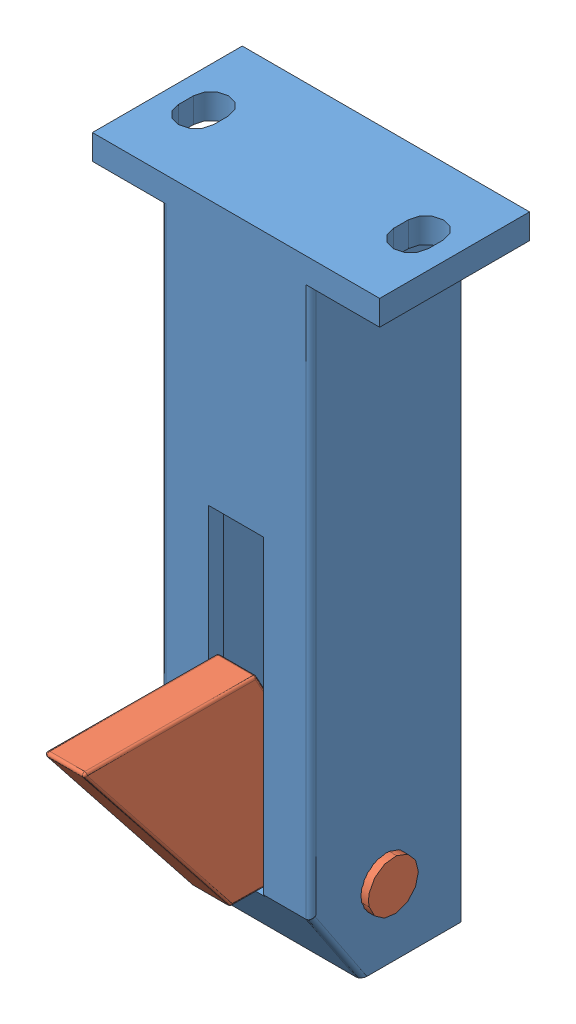
SolidWorks assembly 防坠安全器, configuration Default. Lengths in mm.
Overall size (115 260 128.97).
2 component instances, 2 part files, 4 mates.
Components (placement in the parent):
- 防坠器外壳-1: 防坠器外壳 [Default] at (141.0798 312.8832 146.3772) size (115 260 60)
- 零件4-1: 零件4 [Default] at (111.0798 -25.3956 233.3635) x (0 0.00518 0.999987) z (-1 0 0) size (108.92 85 66)
Mates (geometry in assembly coordinates):
- 同心1: concentric: cylinder of 防坠器外壳-1 through (82.7955 91.8832 116.3772) axis (1 0 0) radius 10; cylinder of 零件4-1 through (108.0798 91.8832 116.3772) axis (1 0 0) radius 9.9963
- 距离1: distance = 3 mm: plane of 防坠器外壳-1 through (111.0798 62.8832 144.3772) normal (-1 0 0); plane of 零件4-1 through (108.0798 91.8832 116.3772) normal (-1 0 0)
- 常闭: parallel: plane of 零件4-1; plane of 防坠器外壳-1 through (113.0798 62.8832 144.3772) normal (0 -1 0)
- 打开: planar angle = 0.872665 rad: plane of 零件4-1 through (149.0798 193.0376 145.9883) normal (0 0.999987 -0.00518); plane of 防坠器外壳-1 through (83.5798 322.8832 146.3772) normal (0 0 1)
